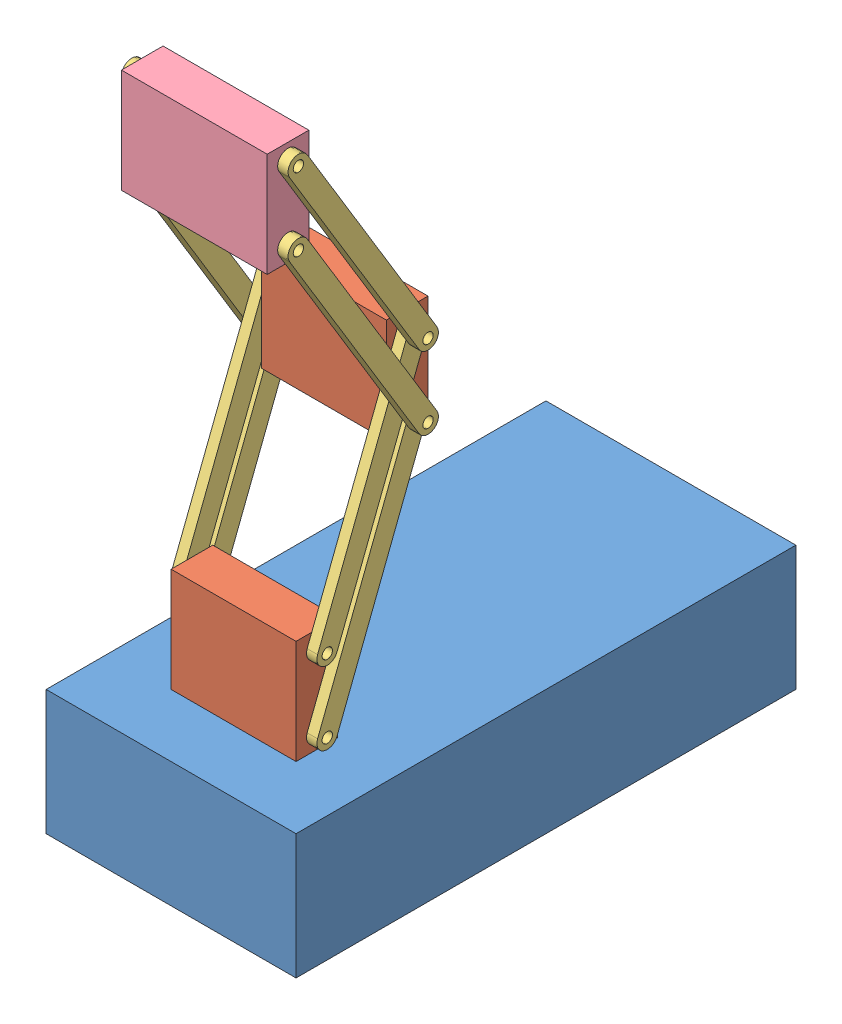
SolidWorks assembly fake robot, configuration Default. Lengths in mm.
Overall size (304.8 824.2 609.6).
12 component instances, 4 part files, 21 mates.
Components (placement in the parent):
- fake chasis box-1: fake chasis box [Default] at (-139.4527 -85.0472 303.9786) size (304.8 152.4 609.6)
- fake link holder-1: fake link holder [Default] at (-63.2527 67.3528 227.7786) size (152.4 127 50.8)
- fake link-1: fake link [Default] at (89.1473 86.4028 202.3786) x (0 0.930405 -0.366534) z (0 -0.366534 -0.930405) size (330.2 12.7 27.05)
- fake link-2: fake link [Default] at (89.1473 175.3028 202.3786) x (0 0.930405 -0.366534) z (0 -0.366534 -0.930405) size (330.2 12.7 27.05)
- fake link-3: fake link [Default] at (-75.9527 175.3028 202.3786) x (0 0.930405 -0.366534) z (0 -0.366534 -0.930405) size (330.2 12.7 27.05)
- fake link-4: fake link [Default] at (-75.9527 86.4028 202.3786) x (0 0.930405 -0.366534) z (0 -0.366534 -0.930405) size (330.2 12.7 27.05)
- fake link holder-2: fake link holder [Default] at (-63.2527 351.5462 117.5973) size (152.4 127 50.8)
- fake link-5: fake link [Default] at (101.8473 631.2067 250.273) x (0 -0.85781 -0.513968) z (0 -0.513968 0.85781) size (330.2 12.7 27.05)
- fake link-6: fake link [Default] at (101.8473 720.1067 250.273) x (0 -0.85781 -0.513968) z (0 -0.513968 0.85781) size (330.2 12.7 27.05)
- fake link-7: fake link [Default] at (-88.6527 720.1067 250.273) x (0 -0.85781 -0.513968) z (0 -0.513968 0.85781) size (330.2 12.7 27.05)
- fake link-8: fake link [Default] at (-75.9527 370.5962 92.1973) x (0 0.852183 0.523244) z (0 -0.523244 0.852183) size (330.2 12.7 27.05)
- fake link holder but bigger-1: fake link holder but bigger [Default] at (-75.9527 612.1567 275.673) size (177.8 127 50.8)
Mates (geometry in assembly coordinates):
- Coincident1: coincident anti-aligned: plane of fake chasis box-1 through (-139.4527 67.3528 303.9786) normal (0 1 0); plane of fake link holder-1 through (-63.2527 67.3528 227.7786) normal (0 -1 0)
- Distance1: distance = 76.2 mm: line of fake link holder-1 through (89.1473 67.3528 227.7786) axis (0 0 -1); line of fake chasis box-1 through (165.3473 67.3528 303.9786) axis (0 0 -1)
- Distance2: distance = 76.2 mm: line of fake link holder-1 through (-63.2527 67.3528 227.7786) axis (1 0 0); line of fake chasis box-1 through (-139.4527 67.3528 303.9786) axis (1 0 0)
- Coincident4: coincident anti-aligned: circle of fake link holder-1; circle of fake link-1
- Coincident5: coincident anti-aligned: circle of fake link holder-1; circle of fake link-2
- Parallel1: parallel anti-aligned: plane of fake link-1 through (101.8473 90.9936 214.2198) normal (0 0.361482 0.932379); plane of fake link-2 through (101.8473 170.712 190.5373) normal (0 -0.361482 -0.932379)
- Coincident7: coincident anti-aligned: circle of fake link holder-1; circle of fake link-4
- Coincident8: coincident anti-aligned: circle of fake link holder-1; circle of fake link-3
- Parallel2: parallel anti-aligned: plane of fake link-3 through (-63.2527 170.712 190.5373) normal (0 -0.361482 -0.932379); plane of fake link-4 through (-63.2527 90.9936 214.2198) normal (0 0.361482 0.932379)
- Coincident10: coincident anti-aligned: circle of fake link-2; circle of fake link holder-2
- Coincident11: coincident anti-aligned: circle of fake link-1; circle of fake link holder-2
- Coincident12: coincident aligned: cylinder of fake link-3 through (-63.2527 459.4962 92.1973) axis (-1 0 0) radius 6.35; circle of fake link holder-2
- Coincident13: coincident aligned: circle of fake link-3; circle of fake link-7
- Coincident14: coincident anti-aligned: circle of fake link-4; circle of fake link-8
- Parallel3: parallel anti-aligned: plane of fake link-7 through (-75.9527 713.5203 261.1316) normal (0 -0.518613 0.855009); plane of fake link-8 through (-88.6527 377.1825 81.3387) normal (0 0.518613 -0.855009)
- Coincident16: coincident aligned: circle of fake link-2; circle of fake link-6
- Coincident17: coincident aligned: circle of fake link-1; circle of fake link-5
- Parallel4: parallel anti-aligned: plane of fake link-5 through (114.5473 637.7931 239.4143) normal (0 0.518613 -0.855009); plane of fake link-6 through (114.5473 713.5203 261.1316) normal (0 -0.518613 0.855009)
- Coincident19: coincident anti-aligned: circle of fake link-7; circle of fake link holder but bigger-1
- Coincident20: coincident anti-aligned: circle of fake link-6; circle of fake link holder but bigger-1
- Coincident21: coincident aligned: circle of fake link-8; circle of fake link holder but bigger-1
